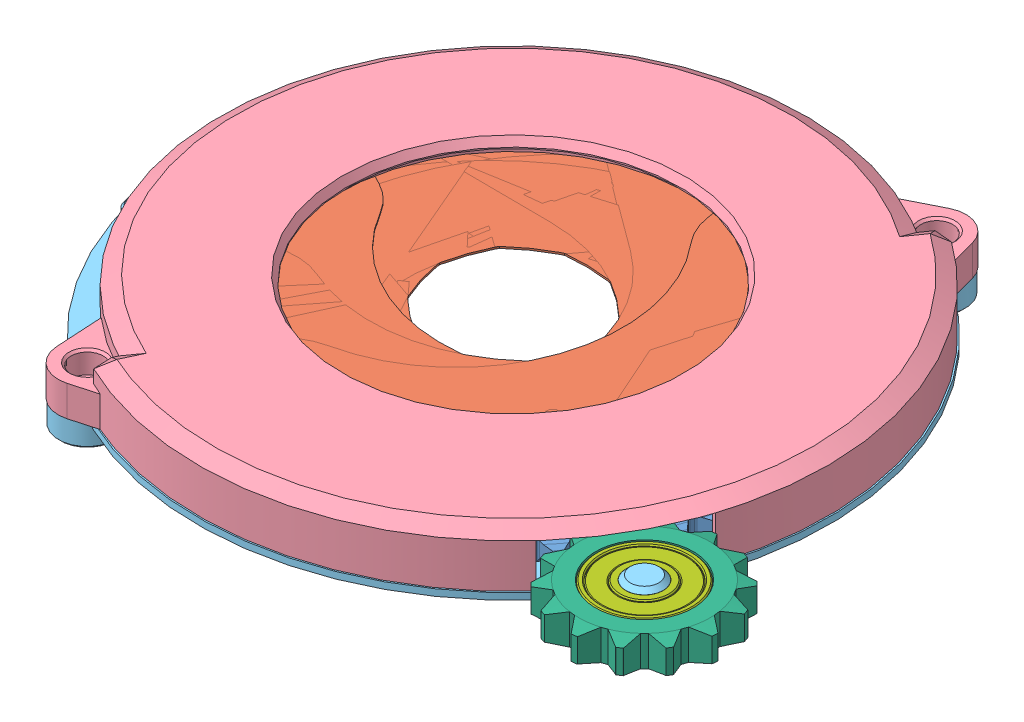
SolidWorks assembly Assem2, configuration Default. Lengths in mm.
Overall size (216.01 17.5 214.15).
35 component instances, 7 part files, 41 mates.
Components (placement in the parent):
- Baseplate-1: Baseplate [Default] at (47.1426 132.5786 181.8484) x (0.65727 0 0.753655) z (-0.753655 0 0.65727) size (130.03 5.34 126.67)
- Assem Iris Arc-1: Assem Iris Arc [Default] at (43.1776 73.5561 77.5804) x (0.972659 0 0.232239) z (-0.232239 0 0.972659) size (110.3 8 64.5)
  - Iris Arc Pinless-1: Iris Arc Pinless [Default] at (32.5479 61.7225 121.1746) size (110.3 5.65 64.5)
  - Iris Arc Pin-1: Iris Arc Pin [Default] at (-17.4521 61.5225 121.1746) size (2.7 4 2.7)
- Hole Plate-1: Hole Plate [Default] at (47.1426 138.5786 181.8484) x (0.906308 0 0.422618) z (-0.422618 0 0.906308) size (138.33 12 154.64)
- Assem Iris Arc-2: Assem Iris Arc [Default] at (-17.3524 73.5561 99.8244) x (0.923404 0 -0.383829) z (0.383829 0 0.923404) size (110.3 8 64.5)
  - Iris Arc Pinless-1: Iris Arc Pinless [Default] at (32.5479 61.7225 121.1746) size (110.3 5.65 64.5)
  - Iris Arc Pin-1: Iris Arc Pin [Default] at (-17.4521 61.5225 121.1746) size (2.7 4 2.7)
- Assem Iris Arc-15: Assem Iris Arc [Default] at (145.0821 73.5561 145.8569) x (0.079696 0 0.996819) z (-0.996819 0 0.079696) size (110.3 8 64.5)
  - Iris Arc Pinless-1: Iris Arc Pinless [Default] at (32.5479 61.7225 121.1746) size (110.3 5.65 64.5)
  - Iris Arc Pin-1: Iris Arc Pin [Default] at (-17.4521 61.5225 121.1746) size (2.7 4 2.7)
- Assem Iris Arc-14: Assem Iris Arc [Default] at (105.222 73.5561 95.1633) x (0.650391 0 0.7596) z (-0.7596 0 0.650391) size (110.3 8 64.5)
  - Iris Arc Pinless-1: Iris Arc Pinless [Default] at (32.5479 61.7225 121.1746) size (110.3 5.65 64.5)
  - Iris Arc Pin-1: Iris Arc Pin [Default] at (-17.4521 61.5225 121.1746) size (2.7 4 2.7)
- Assem Iris Arc-13: Assem Iris Arc [Default] at (-53.2474 73.5561 153.3987) x (0.52144 0 -0.853288) z (0.853288 0 0.52144) size (110.3 8 64.5)
  - Iris Arc Pinless-1: Iris Arc Pinless [Default] at (32.5479 61.7225 121.1746) size (110.3 5.65 64.5)
  - Iris Arc Pin-1: Iris Arc Pin [Default] at (-17.4521 61.5225 121.1746) size (2.7 4 2.7)
- Assem Iris Arc-12: Assem Iris Arc [Default] at (147.5325 75.1561 210.2981) x (-0.52144 0 0.853288) z (-0.853288 0 -0.52144) size (110.3 8 64.5)
  - Iris Arc Pinless-1: Iris Arc Pinless [Default] at (32.5479 61.7225 121.1746) size (110.3 5.65 64.5)
  - Iris Arc Pin-1: Iris Arc Pin [Default] at (-17.4521 61.5225 121.1746) size (2.7 4 2.7)
- Assem Iris Arc-11: Assem Iris Arc [Default] at (111.6375 75.1561 263.8724) x (-0.923404 0 0.383829) z (-0.383829 0 -0.923404) size (110.3 8 64.5)
  - Iris Arc Pinless-1: Iris Arc Pinless [Default] at (32.5479 61.7225 121.1746) size (110.3 5.65 64.5)
  - Iris Arc Pin-1: Iris Arc Pin [Default] at (-17.4521 61.5225 121.1746) size (2.7 4 2.7)
- Assem Iris Arc-10: Assem Iris Arc [Default] at (51.1075 75.1561 286.1164) x (-0.972659 0 -0.232239) z (0.232239 0 -0.972659) size (110.3 8 64.5)
  - Iris Arc Pinless-1: Iris Arc Pinless [Default] at (32.5479 61.7225 121.1746) size (110.3 5.65 64.5)
  - Iris Arc Pin-1: Iris Arc Pin [Default] at (-17.4521 61.5225 121.1746) size (2.7 4 2.7)
- Assem Iris Arc-9: Assem Iris Arc [Default] at (-10.9369 73.5561 268.5335) x (-0.650391 0 -0.7596) z (0.7596 0 -0.650391) size (110.3 8 64.5)
  - Iris Arc Pinless-1: Iris Arc Pinless [Default] at (32.5479 61.7225 121.1746) size (110.3 5.65 64.5)
  - Iris Arc Pin-1: Iris Arc Pin [Default] at (-17.4521 61.5225 121.1746) size (2.7 4 2.7)
- Assem Iris Arc-16: Assem Iris Arc [Default] at (-50.7969 73.5561 217.8399) x (-0.079696 0 -0.996819) z (0.996819 0 -0.079696) size (110.3 8 64.5)
  - Iris Arc Pinless-1: Iris Arc Pinless [Default] at (32.5479 61.7225 121.1746) size (110.3 5.65 64.5)
  - Iris Arc Pin-1: Iris Arc Pin [Default] at (-17.4521 61.5225 121.1746) size (2.7 4 2.7)
- Static Base-1: Static Base [Default] at (47.1426 130.0786 181.8484) x (-0.5 0 0.866025) z (-0.866025 0 -0.5) size (154.9 14 160)
- Small Gear-1: Small Gear [Default] at (117.9401 130.5786 222.7234) x (-0.993039 0 0.117789) z (-0.117789 0 -0.993039) size (35.8 7.03 36.43)
- Bearing-1: Bearing [Default] at (117.9401 134.0786 222.7234) size (21.95 7 21.95)
Mates (geometry in assembly coordinates):
- Coincident1: coincident anti-aligned: plane of Baseplate-1 through (47.1426 135.0786 181.8484) normal (0 1 0); plane of Assem Iris Arc-1/Iris Arc Pinless-1 through (71.1861 135.0786 197.9862) normal (0 -1 0)
- Slot1: slot anti-aligned: cylinder of Assem Iris Arc-1/Iris Arc Pinless-1 through (95.678 131.0786 192.9716) axis (0 1 0) radius 1.2; plane of Baseplate-1 through (47.4218 135.0786 180.63) normal (-0.223386 0 0.97473); cylinder of Baseplate-1 through (93.2798 135.0786 192.422) axis (0 -1 0) radius 1.25
- Distance1: distance = 2 mm anti-aligned: plane of Hole Plate-1 through (47.1426 137.0786 181.8484) normal (0 -1 0); plane of Baseplate-1 through (47.1426 135.0786 181.8484) normal (0 1 0)
- Concentric1: concentric aligned: cylinder of Baseplate-1 through (47.1426 135.0786 181.8484) axis (0 -1 0) radius 63.3333; cylinder of Hole Plate-1 through (47.1426 140.0786 181.8484) axis (0 -1 0) radius 60
- Concentric2: concentric aligned: cylinder of Assem Iris Arc-1/Iris Arc Pin-1 through (-1.9388 139.0786 191.3888) axis (0 -1 0) radius 1.35; cylinder of Hole Plate-1 through (-1.9388 140.0786 191.3888) axis (0 -1 0) radius 1.55
- Concentric3: concentric aligned: cylinder of Hole Plate-1 through (13.0426 140.0786 218.4161) axis (0 -1 0) radius 1.55; cylinder of Assem Iris Arc-2/Iris Arc Pin-1 through (13.0426 139.0786 218.4161) axis (0 -1 0) radius 1.35
- Coincident3: coincident anti-aligned: plane of Baseplate-1 through (47.1426 135.0786 181.8484) normal (0 1 0); plane of Assem Iris Arc-2/Iris Arc Pinless-1 through (76.0797 135.0786 180.7717) normal (0 -1 0)
- Concentric4: concentric aligned: cylinder of Hole Plate-1 through (41.0491 140.0786 231.4757) axis (0 -1 0) radius 1.55; cylinder of Assem Iris Arc-13/Iris Arc Pin-1 through (41.0491 139.0786 231.4757) axis (0 -1 0) radius 1.35
- Coincident4: coincident anti-aligned: plane of Baseplate-1 through (47.1426 135.0786 181.8484) normal (0 1 0); plane of Assem Iris Arc-13/Iris Arc Pinless-1 through (69.9204 135.0786 163.9685) normal (0 -1 0)
- Concentric5: concentric aligned: cylinder of Hole Plate-1 through (1.8272 140.0786 160.7175) axis (0 -1 0) radius 1.55; cylinder of Assem Iris Arc-14/Iris Arc Pin-1 through (1.8272 139.0786 160.7175) axis (0 -1 0) radius 1.35
- Coincident5: coincident anti-aligned: plane of Baseplate-1 through (47.1426 135.0786 181.8484) normal (0 1 0); plane of Assem Iris Arc-14/Iris Arc Pinless-1 through (57.1086 135.0786 209.0366) normal (0 -1 0)
- Concentric6: concentric aligned: cylinder of Hole Plate-1 through (22.9021 140.0786 138.1174) axis (0 -1 0) radius 1.55; cylinder of Assem Iris Arc-15/Iris Arc Pin-1 through (22.9021 139.0786 138.1174) axis (0 -1 0) radius 1.35
- Coincident6: coincident anti-aligned: plane of Baseplate-1 through (47.1426 135.0786 181.8484) normal (0 1 0); plane of Assem Iris Arc-15/Iris Arc Pinless-1 through (39.2244 135.0786 209.702) normal (0 -1 0)
- Slot2: slot anti-aligned: cylinder of Assem Iris Arc-2/Iris Arc Pinless-1 through (92.9466 131.0786 162.3189) axis (0 1 0) radius 1.2; plane of Baseplate-1 through (47.6328 135.0786 182.9982) normal (-0.392209 0 -0.919876); cylinder of Baseplate-1 through (103.6492 135.0786 157.7556) axis (0 -1 0) radius 1.25
- Slot3: slot anti-aligned: cylinder of Assem Iris Arc-13/Iris Arc Pinless-1 through (72.7196 131.0786 139.1257) axis (0 1 0) radius 1.2; plane of Baseplate-1 through (46.0701 135.0786 181.2063) normal (0.857993 0 0.513661); cylinder of Baseplate-1 through (71.4558 135.0786 141.2367) axis (0 -1 0) radius 1.25
- Slot4: slot anti-aligned: cylinder of Assem Iris Arc-14/Iris Arc Pinless-1 through (79.8705 131.0786 219.3757) axis (0 1 0) radius 1.2; plane of Baseplate-1 through (48.0846 135.0786 181.0268) normal (-0.753655 0 0.65727); cylinder of Baseplate-1 through (78.2533 135.0786 217.5214) axis (0 -1 0) radius 1.25
- Slot5: slot anti-aligned: cylinder of Assem Iris Arc-15/Iris Arc Pinless-1 through (51.562 131.0786 231.4456) axis (0 1 0) radius 1.2; plane of Baseplate-1 through (48.3876 135.0786 181.7375) normal (-0.996053 0 0.088755); cylinder of Baseplate-1 through (51.3436 135.0786 228.9949) axis (0 -1 0) radius 1.25
- Slot6: slot anti-aligned: cylinder of Assem Iris Arc-12/Iris Arc Pinless-1 through (21.5655 132.6786 224.5711) axis (0 1 0) radius 1.2; plane of Baseplate-1 through (48.215 135.0786 182.4905) normal (-0.857993 0 -0.513661); cylinder of Baseplate-1 through (22.8293 135.0786 222.4601) axis (0 -1 0) radius 1.25
- Slot7: slot anti-aligned: cylinder of Assem Iris Arc-11/Iris Arc Pinless-1 through (1.3385 132.6786 201.3779) axis (0 1 0) radius 1.2; plane of Baseplate-1 through (47.6328 135.0786 182.9982) normal (-0.392209 0 -0.919876); cylinder of Baseplate-1 through (3.6018 135.0786 200.413) axis (0 -1 0) radius 1.25
- Slot8: slot anti-aligned: cylinder of Assem Iris Arc-10/Iris Arc Pinless-1 through (-1.3929 132.6786 170.7252) axis (0 1 0) radius 1.2; plane of Baseplate-1 through (46.8633 135.0786 183.0668) normal (0.223386 0 -0.97473); cylinder of Baseplate-1 through (1.0053 135.0786 171.2748) axis (0 -1 0) radius 1.25
- Slot9: slot anti-aligned: cylinder of Assem Iris Arc-9/Iris Arc Pinless-1 through (14.4146 131.0786 144.3211) axis (0 1 0) radius 1.2; plane of Baseplate-1 through (46.2005 135.0786 182.67) normal (0.753655 0 -0.65727); cylinder of Baseplate-1 through (16.0318 135.0786 146.1754) axis (0 -1 0) radius 1.25
- Slot10: slot anti-aligned: cylinder of Assem Iris Arc-16/Iris Arc Pinless-1 through (42.7231 131.0786 132.2512) axis (0 1 0) radius 1.2; plane of Baseplate-1 through (45.8975 135.0786 181.9593) normal (0.996053 0 -0.088755); cylinder of Baseplate-1 through (42.9415 135.0786 134.7019) axis (0 -1 0) radius 1.25
- Coincident7: coincident anti-aligned: plane of Baseplate-1 through (47.1426 135.0786 181.8484) normal (0 1 0); plane of Assem Iris Arc-16/Iris Arc Pinless-1 through (55.0607 135.0786 153.9948) normal (0 -1 0)
- Coincident8: coincident anti-aligned: plane of Baseplate-1 through (47.1426 135.0786 181.8484) normal (0 1 0); plane of Assem Iris Arc-9/Iris Arc Pinless-1 through (37.1765 135.0786 154.6602) normal (0 -1 0)
- Coincident10: coincident anti-aligned: plane of Hole Plate-1 through (47.1426 137.0786 181.8484) normal (0 -1 0); plane of Assem Iris Arc-10/Iris Arc Pinless-1 through (23.0991 137.0786 165.7106) normal (0 1 0)
- Coincident11: coincident anti-aligned: plane of Hole Plate-1 through (47.1426 137.0786 181.8484) normal (0 -1 0); plane of Assem Iris Arc-11/Iris Arc Pinless-1 through (18.2054 137.0786 182.9251) normal (0 1 0)
- Coincident12: coincident anti-aligned: plane of Hole Plate-1 through (47.1426 137.0786 181.8484) normal (0 -1 0); plane of Assem Iris Arc-12/Iris Arc Pinless-1 through (24.3647 137.0786 199.7283) normal (0 1 0)
- Concentric7: concentric aligned: cylinder of Hole Plate-1 through (53.236 140.0786 132.2211) axis (0 -1 0) radius 1.55; cylinder of Assem Iris Arc-12/Iris Arc Pin-1 through (53.236 140.6786 132.2211) axis (0 -1 0) radius 1.35
- Concentric8: concentric aligned: cylinder of Hole Plate-1 through (81.2425 140.0786 145.2807) axis (0 -1 0) radius 1.55; cylinder of Assem Iris Arc-11/Iris Arc Pin-1 through (81.2425 140.6786 145.2807) axis (0 -1 0) radius 1.35
- Concentric9: concentric aligned: cylinder of Hole Plate-1 through (96.2239 140.0786 172.3079) axis (0 -1 0) radius 1.55; cylinder of Assem Iris Arc-10/Iris Arc Pin-1 through (96.2239 140.6786 172.3079) axis (0 -1 0) radius 1.35
- Concentric10: concentric aligned: cylinder of Hole Plate-1 through (92.4579 140.0786 202.9793) axis (0 -1 0) radius 1.55; cylinder of Assem Iris Arc-9/Iris Arc Pin-1 through (92.4579 139.0786 202.9793) axis (0 -1 0) radius 1.35
- Concentric11: concentric aligned: cylinder of Hole Plate-1 through (71.383 140.0786 225.5794) axis (0 -1 0) radius 1.55; cylinder of Assem Iris Arc-16/Iris Arc Pin-1 through (71.383 139.0786 225.5794) axis (0 -1 0) radius 1.35
- Concentric12: concentric anti-aligned: circle of Hole Plate-1; circle of Iris Arc-7
- Coincident13: coincident anti-aligned: plane of Hole Plate-1 through (47.1426 130.0786 181.8484) normal (0 -1 0); plane of Static Base-1 through (47.1426 130.0786 181.8484) normal (0 1 0)
- Concentric13: concentric aligned: cylinder of Baseplate-1 through (47.1426 132.0786 181.8484) axis (0 -1 0) radius 45.0833; cylinder of Static Base-1 through (47.1426 132.8286 181.8484) axis (0 -1 0) radius 44.75
- Width1: width aligned: plane of Static Base-1 through (92.3302 94.8936 158.9816) normal (0.892261 0 -0.45152); plane of Hole Plate-1 through (49.9332 94.8936 232.4154) normal (0.055102 0 0.998481); plane of Static Base-1 through (54.6426 170.5893 168.858) normal (-0.5 0 0.866025); plane of Hole Plate-1 through (39.6426 170.5893 194.8388) normal (0.5 0 -0.866025)
- Coincident14: coincident anti-aligned: plane of Static Base-1 through (117.9401 130.5786 222.7234) normal (0 1 0); plane of Small Gear-1 through (117.9401 130.5786 222.7234) normal (0 -1 0)
- Concentric14: concentric aligned: cylinder of Static Base-1 through (117.9401 138.5786 222.7234) axis (0 -1 0) radius 4.25; cylinder of Small Gear-1 through (117.9401 137.5942 222.7234) axis (0 -1 0) radius 11.15
- GearMate1: gear = 126.6667 : 30 mm: circle of Small Gear-1; cylinder of Baseplate-1 through (47.1426 135.0786 181.8484) axis (0 -1 0) radius 63.3333
- Coincident15: coincident anti-aligned: circle of Static Base-1; plane of Bearing-1 through (117.9401 130.5786 222.7234) normal (0 -1 0)
- Concentric15: concentric aligned: cylinder of Static Base-1 through (117.9401 138.5786 222.7234) axis (0 -1 0) radius 4.25; cylinder of Bearing-1 through (117.9401 137.5786 222.7234) axis (0 -1 0) radius 4.025
